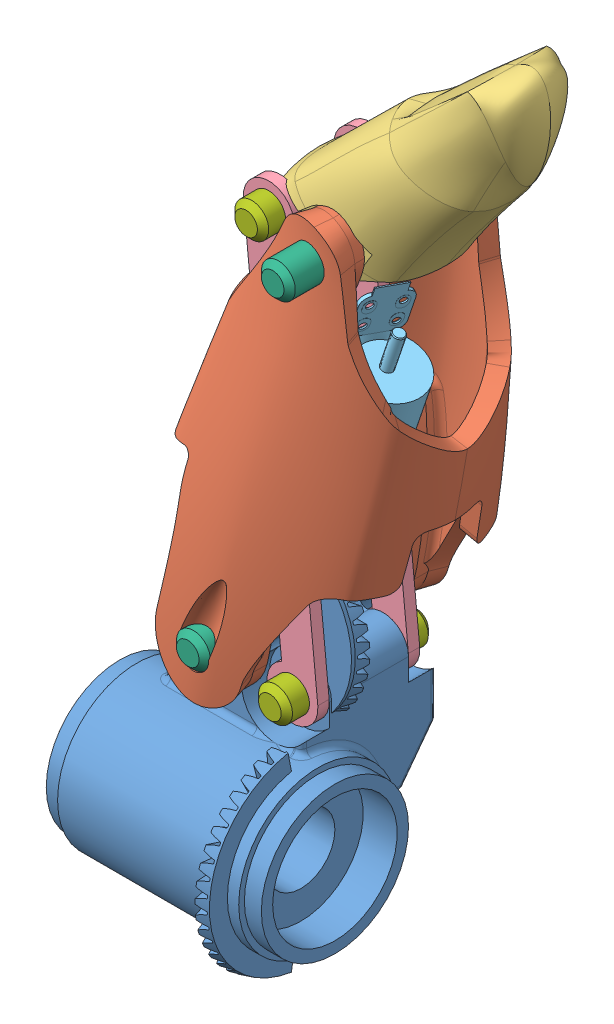
SolidWorks assembly 02-005, configuration 默认. Lengths in mm.
Overall size (34.23 77.3 25.51).
13 component instances, 9 part files, 16 mates.
Components (placement in the parent):
- 01-47-1: 01-47 [默认] at origin size (19 30.82 20.87)
- 01-011-02-1: 01-011-02 [默认] at (8.1022 20.2106 16.6669) x (0 0 1) z (-0.236988 -0.971513 0) size (21.28 21.24 40.42)
- 01-012-1: 01-012 [默认] at (6.5104 30.5806 16.6669) x (0 0 1) z (-0.331416 -0.943485 0) size (10.01 16.64 26.66)
- 01-013-1: 01-013 [默认] at (11.8224 20.3577 12.1669) x (0 0 -1) z (0.099717 -0.995016 0) size (1 6 40.5)
- 01-013-2: 01-013 [默认] at (11.8224 20.3577 20.1669) x (0 0 -1) z (0.099717 -0.995016 0) size (1 6 40.5)
- FDM0620-2R-_-30-1: FDM0620-2R-_-30 [默认] at (12.6355 36.0495 16.6669) x (-0.885558 0.299897 -0.354751) z (-0.320759 -0.947161 0) size (6 6 19.98)
- 01-035-1: 01-035 [默认] at (8.0724 24.3577 23.6669) size (3 3 14)
- 01-035-2: 01-035 [默认] at (15.5771 56.392 23.6669) x (0.965306 0.261122 0) z (0 0 1) size (3 3 14)
- 01-037-1: 01-037 [默认] at (11.8224 20.3577 23.1669) size (3 3 13)
- 01-037-2: 01-037 [默认] at (9.7251 56.3278 23.1669) x (0.971074 0.23878 0) z (0 0 1) size (3 3 13)
- 01-038_Metric - Straight bevel pinion 0.4M12PT 40GT 20PA 2FW ---12O5H6MD1N-1: 01-038_Metric - Straight bevel pinion 0.4M12PT 40GT 20PA 2FW ---12O5H6MD1N [默认] at (11.3903 32.3726 16.6669) x (-0.320759 -0.947161 0) z (-0.736911 0.249557 0.628239) size (2.25 5.54 5.54)
- 01-49_AFBMA 20.1 - 18-5 - 10,SI,NC,10_68-1: 01-49_AFBMA 20.1 - 18-5 - 10,SI,NC,10_68 [默认] at (-0.4276 10.3577 22.6669) size (3.01 11 11) (hidden)
- 01-49_AFBMA 20.1 - 18-5 - 10,SI,NC,10_68-2: 01-49_AFBMA 20.1 - 18-5 - 10,SI,NC,10_68 [默认] at (15.5724 10.3577 22.6669) size (3.01 11 11) (hidden)
Mates (geometry in assembly coordinates):
- Concentric1: concentric aligned: cylinder of 01-013-2 through (11.8224 20.3577 21.1669) axis (0 0 -1) radius 1; cylinder of 01-037-1 through (11.8224 20.3577 10.1669) axis (0 0 -1) radius 1
- Coincident1: coincident anti-aligned: plane of 01-013-2 through (11.8224 20.3577 21.1669) normal (0 0 1); plane of 01-037-1 through (11.8224 21.8577 21.1669) normal (0 0 -1)
- Concentric2: concentric aligned: cylinder of 01-013-1 through (11.8224 20.3577 13.1669) axis (0 0 -1) radius 2.25; cylinder of 01-037-1 through (11.8224 20.3577 10.1669) axis (0 0 -1) radius 1.5
- Coincident2: coincident anti-aligned: plane of 01-47-1 through (11.8224 20.3577 13.1669) normal (0 0 -1); plane of 01-013-1 through (11.8224 20.3577 13.1669) normal (0 0 1)
- Lock1: lock: unknown of 01-013-2; unknown of 01-037-2
- Concentric3: concentric aligned: cylinder of 01-012-1 through (9.7251 56.3278 21.6706) axis (0 0 -1) radius 0.75; cylinder of 01-037-2 through (9.7251 56.3278 10.1669) axis (0 0 -1) radius 1
- Concentric4: concentric aligned: cylinder of 01-013-1 through (9.7251 56.3278 13.1669) axis (0 0 -1) radius 1; cylinder of 01-037-2 through (9.7251 56.3278 10.1669) axis (0 0 -1) radius 1
- Concentric5: concentric aligned: cylinder of 01-013-1 through (9.7251 56.3278 13.1669) axis (0 0 -1) radius 2.25; cylinder of 01-013-2 through (9.7251 56.3278 21.1669) axis (0 0 -1) radius 2.25
- Lock2: lock: unknown of 01-011-02-1; unknown of 01-035-2
- Concentric6: concentric anti-aligned: cylinder of 01-012-1 through (15.5771 56.392 22.8125) axis (0 0 -1) radius 1; cylinder of 01-035-2 through (15.5771 56.392 23.6669) axis (0 0 1) radius 1.5
- Concentric7: concentric anti-aligned: cylinder of 01-011-02-1 through (8.0724 24.3577 27.306) axis (0 0 -1) radius 1.5; cylinder of 01-035-1 through (8.0724 24.3577 23.6669) axis (0 0 1) radius 1.5
- Width1: width aligned: plane of 01-013-1 through (11.8224 20.3577 13.1669) normal (0 0 1); plane of 01-013-2 through (11.8224 20.3577 20.1669) normal (0 0 -1); plane of 01-012-1 through (9.7251 56.3278 20.1669) normal (0 0 1); plane of 01-012-1 through (9.7251 56.3278 13.1669) normal (0 0 -1)
- Width2: width anti-aligned: plane of 01-47-1 through (14.0724 26.3577 22.6669) normal (0 0 1); plane of 01-47-1 through (14.0724 14.3577 10.6669) normal (0 0 -1); plane of 01-011-02-1 through (4.9595 22.2819 22.6669) normal (0 0 -1); plane of 01-011-02-1 through (4.9595 22.2819 10.6669) normal (0 0 1)
- Concentric8: concentric anti-aligned: cylinder of 01-011-02-1 through (9.2996 26.199 16.6669) axis (0.320759 0.947161 0) radius 2; cylinder of FDM0620-2R-_-30-1 through (12.5072 35.6706 16.6669) axis (-0.320759 -0.947161 0) radius 2.25
- Coincident3: coincident anti-aligned: plane of 01-011-02-1 through (15.8223 34.548 19.6669) normal (0.320759 0.947161 0); plane of FDM0620-2R-_-30-1 through (12.5072 35.6706 16.6669) normal (-0.320759 -0.947161 0)
- Concentric9: concentric aligned: cylinder of FDM0620-2R-_-30-1 through (10.9836 31.1716 16.6669) axis (0.320759 0.947161 0) radius 0.5; cylinder of 01-038_Metric - Straight bevel pinion 0.4M12PT 40GT 20PA 2FW ---12O5H6MD1N-1 through (8.7887 24.6902 16.6669) axis (0.320759 0.947161 0) radius 0.5
